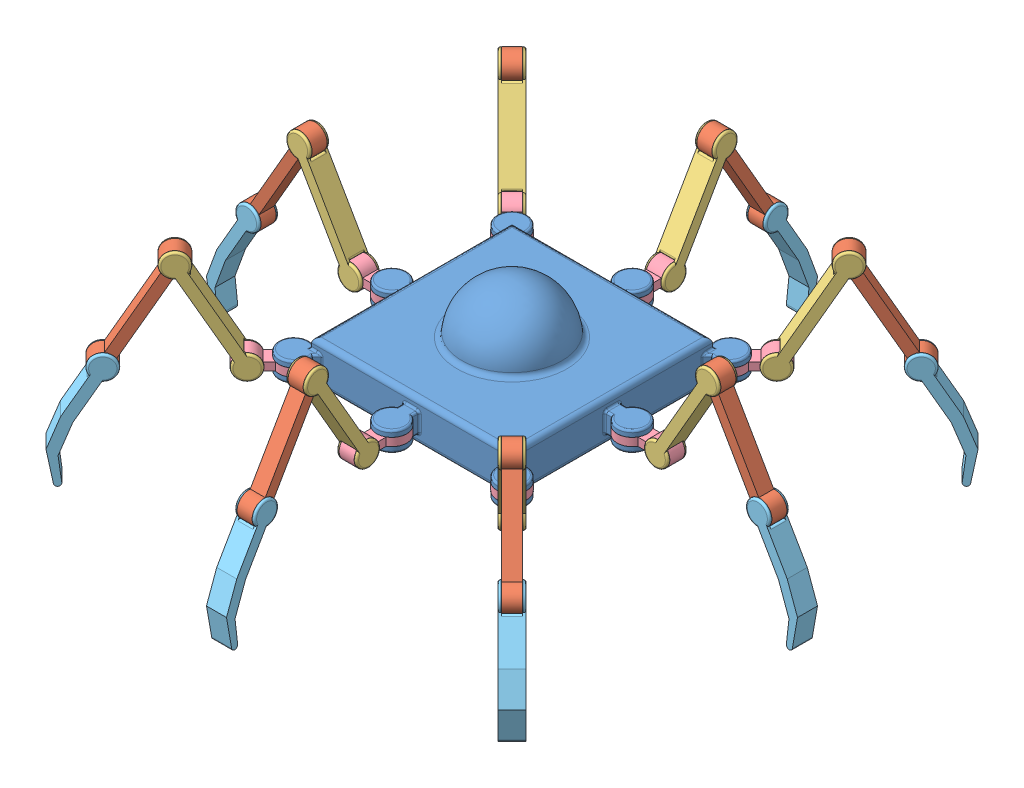
SolidWorks assembly SpiderBot_4Legs, configuration Default. Lengths in mm.
Overall size (634.89 234.57 634.89).
33 component instances, 5 part files, 146 mates.
Components (placement in the parent):
- spider_body-1: spider_body [Default] at (0 150 0) x (0 0 -1) z (0 -1 0) size (270 270 90)
- Link_C-24: Link_C [Default] at (-183.9152 176.5882 -194.5218) x (0.353553 0.866025 0.353553) z (-0.707107 0 0.707107) size (125.82 24 15)
- Link_B-24: Link_B [Default] at (-140.0258 176.5882 -154.1679) x (-0.707107 0 0.707107) z (-0.353553 0.866025 -0.353553) size (20.32 24 125.82)
- Link_A-24: Link_A [Default] at (-108.832 134 -108.832) x (-0.707107 0 -0.707107) z (0 -1 0) size (59.99 30 24)
- Link_D-24: Link_D [Default] at (-232.2874 88.4118 -218.1453) x (0.707107 0 -0.707107) z (0.353553 0.866025 0.353553) size (20.32 36.78 116.49)
- Link_C-26: Link_C [Default] at (-194.5218 176.5882 183.9152) x (0.353553 0.866025 -0.353553) z (0.707107 0 0.707107) size (125.82 24 15)
- Link_B-26: Link_B [Default] at (-154.1679 176.5882 140.0258) x (0.707107 0 0.707107) z (-0.353553 0.866025 0.353553) size (20.32 24 125.82)
- Link_A-26: Link_A [Default] at (-108.832 134 108.832) x (-0.707107 0 0.707107) z (0 -1 0) size (59.99 30 24)
- Link_D-26: Link_D [Default] at (-218.1453 88.4118 232.2874) x (-0.707107 0 -0.707107) z (0.353553 0.866025 -0.353553) size (20.32 36.78 116.49)
- Link_C-27: Link_C [Default] at (183.9152 176.5882 194.5218) x (-0.353553 0.866025 -0.353553) z (0.707107 0 -0.707107) size (125.82 24 15)
- Link_B-27: Link_B [Default] at (140.0258 176.5882 154.1679) x (0.707107 0 -0.707107) z (0.353553 0.866025 0.353553) size (20.32 24 125.82)
- Link_A-27: Link_A [Default] at (108.832 134 108.832) x (0.707107 0 0.707107) z (0 -1 0) size (59.99 30 24)
- Link_D-27: Link_D [Default] at (232.2874 88.4118 218.1453) x (-0.707107 0 0.707107) z (-0.353553 0.866025 -0.353553) size (20.32 36.78 116.49)
- Link_B-33: Link_B [Default] at (154.1679 176.5882 -140.0258) x (-0.707107 0 -0.707107) z (0.353553 0.866025 -0.353553) size (20.32 24 125.82)
- Link_D-31: Link_D [Default] at (218.1453 88.4118 -232.2874) x (0.707107 0 0.707107) z (-0.353553 0.866025 0.353553) size (20.32 36.78 116.49)
- Link_A-31: Link_A [Default] at (108.832 134 -108.832) x (0.707107 0 -0.707107) z (0 -1 0) size (59.99 30 24)
- Link_C-31: Link_C [Default] at (194.5218 176.5882 -183.9152) x (-0.353553 0.866025 0.353553) z (-0.707107 0 -0.707107) size (125.82 24 15)
- Link_D-34: Link_D [Default] at (-284.5923 88.4118 10) x (0 0 -1) z (0.5 0.866025 0) size (20.32 36.78 116.49)
- Link_A-34: Link_A [Default] at (-120 134 0) x (-1 0 0) z (0 -1 0) size (59.99 30 24)
- Link_B-36: Link_B [Default] at (-174.1146 176.5882 -10) x (0 0 1) z (-0.5 0.866025 0) size (20.32 24 125.82)
- Link_C-34: Link_C [Default] at (-233.6836 176.5882 -7.5) x (0.5 0.866025 0) z (0 0 1) size (125.82 24 15)
- Link_A-35: Link_A [Default] at (120 134 0) x (1 0 0) z (0 -1 0) size (59.99 30 24)
- Link_D-35: Link_D [Default] at (284.5923 88.4118 -10) x (0 0 1) z (-0.5 0.866025 0) size (20.32 36.78 116.49)
- Link_C-35: Link_C [Default] at (233.6836 176.5882 7.5) x (-0.5 0.866025 0) z (0 0 -1) size (125.82 24 15)
- Link_B-37: Link_B [Default] at (174.1146 176.5882 10) x (0 0 -1) z (0.5 0.866025 0) size (20.32 24 125.82)
- Link_A-36: Link_A [Default] at (0 134 120) x (0 0 1) z (0 -1 0) size (59.99 30 24)
- Link_D-36: Link_D [Default] at (10 88.4118 284.5923) x (-1 0 0) z (0 0.866025 -0.5) size (20.32 36.78 116.49)
- Link_C-36: Link_C [Default] at (-7.5 176.5882 233.6836) x (0 0.866025 -0.5) z (1 0 0) size (125.82 24 15)
- Link_B-38: Link_B [Default] at (-10 176.5882 174.1146) x (1 0 0) z (0 0.866025 0.5) size (20.32 24 125.82)
- Link_A-37: Link_A [Default] at (0 134 -120) x (0 0 -1) z (0 -1 0) size (59.99 30 24)
- Link_D-37: Link_D [Default] at (-10 88.4118 -284.5923) x (1 0 0) z (0 0.866025 0.5) size (20.32 36.78 116.49)
- Link_C-37: Link_C [Default] at (7.5 176.5882 -233.6836) x (0 0.866025 0.5) z (-1 0 0) size (125.82 24 15)
- Link_B-39: Link_B [Default] at (10 176.5882 -174.1146) x (-1 0 0) z (0 0.866025 -0.5) size (20.32 24 125.82)
Mates (geometry in assembly coordinates):
- Coincident4: coincident anti-aligned: plane of Link_B-2 through (235.0341 -365.5738 720.8033) normal (-1 0 0); plane of Link_C-2 through (235.0341 -453.7502 771.712) normal (1 0 0)
- Concentric4: concentric anti-aligned: cylinder of Link_B-2 through (220.0341 -365.5738 720.8033) axis (1 0 0) radius 4; cylinder of Link_C-2 through (235.0341 -365.5738 720.8033) axis (-1 0 0) radius 4
- Coincident5: coincident anti-aligned: plane of Link_C-2 through (235.0341 -453.7502 771.712) normal (1 0 0); plane of Link_D-2 through (235.0341 -453.7502 771.712) normal (-1 0 0)
- Concentric6: concentric aligned: cylinder of Link_C-2 through (235.0341 -453.7502 771.712) axis (-1 0 0) radius 4; cylinder of Link_D-2 through (235.0341 -453.7502 771.712) axis (-1 0 0) radius 4
- Coincident7: coincident anti-aligned: plane of Link_B-3 through (281.248 -759.0313 934.2797) normal (-1 0 0); plane of Link_C-3 through (281.248 -847.2078 985.1885) normal (1 0 0)
- Concentric7: concentric anti-aligned: cylinder of Link_B-3 through (266.248 -759.0313 934.2797) axis (1 0 0) radius 4; cylinder of Link_C-3 through (281.248 -759.0313 934.2797) axis (-1 0 0) radius 4
- Coincident8: coincident anti-aligned: plane of Link_C-3 through (281.248 -847.2078 985.1885) normal (1 0 0); plane of Link_D-3 through (281.248 -847.2078 985.1885) normal (-1 0 0)
- Concentric9: concentric aligned: cylinder of Link_C-3 through (281.248 -847.2078 985.1885) axis (-1 0 0) radius 4; cylinder of Link_D-3 through (281.248 -847.2078 985.1885) axis (-1 0 0) radius 4
- Coincident10: coincident anti-aligned: plane of Link_B-4 through (178.5336 -465.5708 822.703) normal (-1 0 0); plane of Link_C-4 through (178.5336 -553.7473 873.6117) normal (1 0 0)
- Concentric10: concentric anti-aligned: cylinder of Link_B-4 through (163.5336 -465.5708 822.703) axis (1 0 0) radius 4; cylinder of Link_C-4 through (178.5336 -465.5708 822.703) axis (-1 0 0) radius 4
- Coincident11: coincident anti-aligned: plane of Link_C-4 through (178.5336 -553.7473 873.6117) normal (1 0 0); plane of Link_D-4 through (178.5336 -553.7473 873.6117) normal (-1 0 0)
- Concentric12: concentric aligned: cylinder of Link_C-4 through (178.5336 -553.7473 873.6117) axis (-1 0 0) radius 4; cylinder of Link_D-4 through (178.5336 -553.7473 873.6117) axis (-1 0 0) radius 4
- Coincident13: coincident anti-aligned: plane of Link_B-5 through (262.376 -1013.0932 1106.1332) normal (-1 0 0); plane of Link_C-5 through (262.376 -1101.2696 1157.0419) normal (1 0 0)
- Concentric13: concentric anti-aligned: cylinder of Link_B-5 through (247.376 -1013.0932 1106.1332) axis (1 0 0) radius 4; cylinder of Link_C-5 through (262.376 -1013.0932 1106.1332) axis (-1 0 0) radius 4
- Coincident14: coincident anti-aligned: plane of Link_C-5 through (262.376 -1101.2696 1157.0419) normal (1 0 0); plane of Link_D-5 through (262.376 -1101.2696 1157.0419) normal (-1 0 0)
- Concentric15: concentric aligned: cylinder of Link_C-5 through (262.376 -1101.2696 1157.0419) axis (-1 0 0) radius 4; cylinder of Link_D-5 through (262.376 -1101.2696 1157.0419) axis (-1 0 0) radius 4
- Coincident16: coincident anti-aligned: plane of Link_B-6 through (534.9738 -1642.7072 1309.0583) normal (-1 0 0); plane of Link_C-6 through (534.9738 -1730.8837 1359.9671) normal (1 0 0)
- Concentric16: concentric anti-aligned: cylinder of Link_B-6 through (519.9738 -1642.7072 1309.0583) axis (1 0 0) radius 4; cylinder of Link_C-6 through (534.9738 -1642.7072 1309.0583) axis (-1 0 0) radius 4
- Coincident17: coincident anti-aligned: plane of Link_C-6 through (534.9738 -1730.8837 1359.9671) normal (1 0 0); plane of Link_D-6 through (534.9738 -1730.8837 1359.9671) normal (-1 0 0)
- Concentric18: concentric aligned: cylinder of Link_C-6 through (534.9738 -1730.8837 1359.9671) axis (-1 0 0) radius 4; cylinder of Link_D-6 through (534.9738 -1730.8837 1359.9671) axis (-1 0 0) radius 4
- Coincident19: coincident anti-aligned: plane of Link_B-7 through (-306.3909 -269.9837 1039.0888) normal (-1 0 0); plane of Link_C-7 through (-306.3909 -358.1602 1089.9975) normal (1 0 0)
- Concentric19: concentric anti-aligned: cylinder of Link_B-7 through (-321.3909 -269.9837 1039.0888) axis (1 0 0) radius 4; cylinder of Link_C-7 through (-306.3909 -269.9837 1039.0888) axis (-1 0 0) radius 4
- Coincident20: coincident anti-aligned: plane of Link_C-7 through (-306.3909 -358.1602 1089.9975) normal (1 0 0); plane of Link_D-7 through (-306.3909 -358.1602 1089.9975) normal (-1 0 0)
- Concentric21: concentric aligned: cylinder of Link_C-7 through (-306.3909 -358.1602 1089.9975) axis (-1 0 0) radius 4; cylinder of Link_D-7 through (-306.3909 -358.1602 1089.9975) axis (-1 0 0) radius 4
- Coincident22: coincident anti-aligned: plane of Link_B-8 through (-311.8852 -488.0983 1179.1514) normal (-1 0 0); plane of Link_C-8 through (-311.8852 -576.2747 1230.0601) normal (1 0 0)
- Concentric22: concentric anti-aligned: cylinder of Link_B-8 through (-326.8852 -488.0983 1179.1514) axis (1 0 0) radius 4; cylinder of Link_C-8 through (-311.8852 -488.0983 1179.1514) axis (-1 0 0) radius 4
- Coincident23: coincident anti-aligned: plane of Link_C-8 through (-311.8852 -576.2747 1230.0601) normal (1 0 0); plane of Link_D-8 through (-311.8852 -576.2747 1230.0601) normal (-1 0 0)
- Concentric24: concentric aligned: cylinder of Link_C-8 through (-311.8852 -576.2747 1230.0601) axis (-1 0 0) radius 4; cylinder of Link_D-8 through (-311.8852 -576.2747 1230.0601) axis (-1 0 0) radius 4
- Coincident25: coincident anti-aligned: plane of Link_B-9 through (-611.4857 -390.9688 1327.6493) normal (-1 0 0); plane of Link_C-9 through (-611.4857 -479.1453 1378.558) normal (1 0 0)
- Concentric25: concentric anti-aligned: cylinder of Link_B-9 through (-626.4857 -390.9688 1327.6493) axis (1 0 0) radius 4; cylinder of Link_C-9 through (-611.4857 -390.9688 1327.6493) axis (-1 0 0) radius 4
- Coincident26: coincident anti-aligned: plane of Link_C-9 through (-611.4857 -479.1453 1378.558) normal (1 0 0); plane of Link_D-9 through (-611.4857 -479.1453 1378.558) normal (-1 0 0)
- Concentric27: concentric aligned: cylinder of Link_C-9 through (-611.4857 -479.1453 1378.558) axis (-1 0 0) radius 4; cylinder of Link_D-9 through (-611.4857 -479.1453 1378.558) axis (-1 0 0) radius 4
- Coincident28: coincident anti-aligned: plane of Link_B-10 through (-139.42 -657.5126 1164.5577) normal (-1 0 0); plane of Link_C-10 through (-139.42 -745.689 1215.4664) normal (1 0 0)
- Concentric28: concentric anti-aligned: cylinder of Link_B-10 through (-154.42 -657.5126 1164.5577) axis (1 0 0) radius 4; cylinder of Link_C-10 through (-139.42 -657.5126 1164.5577) axis (-1 0 0) radius 4
- Coincident29: coincident anti-aligned: plane of Link_C-10 through (-139.42 -745.689 1215.4664) normal (1 0 0); plane of Link_D-10 through (-139.42 -745.689 1215.4664) normal (-1 0 0)
- Concentric30: concentric aligned: cylinder of Link_C-10 through (-139.42 -745.689 1215.4664) axis (-1 0 0) radius 4; cylinder of Link_D-10 through (-139.42 -745.689 1215.4664) axis (-1 0 0) radius 4
- Coincident31: coincident anti-aligned: plane of Link_B-11 through (-139.42 -657.5126 1164.5577) normal (-1 0 0); plane of Link_C-11 through (-139.42 -745.689 1215.4664) normal (1 0 0)
- Concentric31: concentric anti-aligned: cylinder of Link_B-11 through (-154.42 -657.5126 1164.5577) axis (1 0 0) radius 4; cylinder of Link_C-11 through (-139.42 -657.5126 1164.5577) axis (-1 0 0) radius 4
- Coincident32: coincident anti-aligned: plane of Link_C-11 through (-139.42 -745.689 1215.4664) normal (1 0 0); plane of Link_D-11 through (-139.42 -745.689 1215.4664) normal (-1 0 0)
- Concentric33: concentric aligned: cylinder of Link_C-11 through (-139.42 -745.689 1215.4664) axis (-1 0 0) radius 4; cylinder of Link_D-11 through (-139.42 -745.689 1215.4664) axis (-1 0 0) radius 4
- Coincident34: coincident anti-aligned: plane of Link_B-12 through (-94.7509 -804.43 1225.1322) normal (-1 0 0); plane of Link_C-12 through (-94.7509 -892.6065 1276.0409) normal (1 0 0)
- Concentric34: concentric anti-aligned: cylinder of Link_B-12 through (-109.7509 -804.43 1225.1322) axis (1 0 0) radius 4; cylinder of Link_C-12 through (-94.7509 -804.43 1225.1322) axis (-1 0 0) radius 4
- Coincident35: coincident anti-aligned: plane of Link_C-12 through (-94.7509 -892.6065 1276.0409) normal (1 0 0); plane of Link_D-12 through (-94.7509 -892.6065 1276.0409) normal (-1 0 0)
- Concentric36: concentric aligned: cylinder of Link_C-12 through (-94.7509 -892.6065 1276.0409) axis (-1 0 0) radius 4; cylinder of Link_D-12 through (-94.7509 -892.6065 1276.0409) axis (-1 0 0) radius 4
- Concentric78: concentric anti-aligned: cylinder of Link_C-24 through (-173.461 218.1765 -162.8544) axis (0.707107 0 -0.707107) radius 4; cylinder of Link_B-24 through (-162.8544 218.1765 -173.461) axis (-0.707107 0 0.707107) radius 4
- Concentric79: concentric anti-aligned: cylinder of Link_B-24 through (-126.8565 130 -137.4631) axis (-0.707107 0 0.707107) radius 4; cylinder of Link_A-24 through (-142.7664 130 -121.5532) axis (0.707107 0 -0.707107) radius 5
- Coincident86: coincident anti-aligned: plane of Link_B-24 through (-137.4631 130 -126.8565) normal (0.707107 0 -0.707107); plane of Link_A-24 through (-123.3209 126 -112.7143) normal (-0.707107 0 0.707107)
- Coincident87: coincident anti-aligned: plane of Link_C-24 through (-198.8522 130 -209.4588) normal (0.707107 0 -0.707107); plane of Link_B-24 through (-162.8544 218.1765 -173.461) normal (-0.707107 0 0.707107)
- Coincident88: coincident anti-aligned: plane of Link_C-24 through (-209.4588 130 -198.8522) normal (-0.707107 0 0.707107); plane of Link_B-24 through (-173.461 218.1765 -162.8544) normal (0.707107 0 -0.707107)
- Coincident89: coincident anti-aligned: plane of Link_C-24 through (-198.8522 130 -209.4588) normal (0.707107 0 -0.707107); plane of Link_D-24 through (-198.8522 130 -209.4588) normal (-0.707107 0 0.707107)
- Concentric80: concentric aligned: cylinder of Link_C-24 through (-209.4588 130 -198.8522) axis (0.707107 0 -0.707107) radius 4; cylinder of Link_D-24 through (-209.4588 130 -198.8522) axis (0.707107 0 -0.707107) radius 4
- Coincident90: coincident anti-aligned: plane of Link_B-24 through (-126.8565 130 -137.4631) normal (-0.707107 0 0.707107); plane of Link_A-24 through (-112.7143 126 -123.3209) normal (0.707107 0 -0.707107)
- Coincident91: coincident anti-aligned: plane of Link_C-24 through (-209.4588 130 -198.8522) normal (-0.707107 0 0.707107); plane of Link_D-24 through (-209.4588 130 -198.8522) normal (0.707107 0 -0.707107)
- Concentric84: concentric anti-aligned: cylinder of Link_C-26 through (-162.8544 218.1765 173.461) axis (-0.707107 0 -0.707107) radius 4; cylinder of Link_B-26 through (-173.461 218.1765 162.8544) axis (0.707107 0 0.707107) radius 4
- Concentric85: concentric anti-aligned: cylinder of Link_B-26 through (-137.4631 130 126.8565) axis (0.707107 0 0.707107) radius 4; cylinder of Link_A-26 through (-121.5532 130 142.7664) axis (-0.707107 0 -0.707107) radius 5
- Coincident98: coincident anti-aligned: plane of Link_B-26 through (-126.8565 130 137.4631) normal (-0.707107 0 -0.707107); plane of Link_A-26 through (-112.7143 126 123.3209) normal (0.707107 0 0.707107)
- Coincident99: coincident anti-aligned: plane of Link_C-26 through (-209.4588 130 198.8522) normal (-0.707107 0 -0.707107); plane of Link_B-26 through (-173.461 218.1765 162.8544) normal (0.707107 0 0.707107)
- Coincident100: coincident anti-aligned: plane of Link_C-26 through (-198.8522 130 209.4588) normal (0.707107 0 0.707107); plane of Link_B-26 through (-162.8544 218.1765 173.461) normal (-0.707107 0 -0.707107)
- Coincident101: coincident anti-aligned: plane of Link_C-26 through (-209.4588 130 198.8522) normal (-0.707107 0 -0.707107); plane of Link_D-26 through (-209.4588 130 198.8522) normal (0.707107 0 0.707107)
- Concentric86: concentric aligned: cylinder of Link_C-26 through (-198.8522 130 209.4588) axis (-0.707107 0 -0.707107) radius 4; cylinder of Link_D-26 through (-198.8522 130 209.4588) axis (-0.707107 0 -0.707107) radius 4
- Coincident102: coincident anti-aligned: plane of Link_B-26 through (-137.4631 130 126.8565) normal (0.707107 0 0.707107); plane of Link_A-26 through (-123.3209 126 112.7143) normal (-0.707107 0 -0.707107)
- Coincident103: coincident anti-aligned: plane of Link_C-26 through (-198.8522 130 209.4588) normal (0.707107 0 0.707107); plane of Link_D-26 through (-198.8522 130 209.4588) normal (-0.707107 0 -0.707107)
- Concentric87: concentric anti-aligned: cylinder of Link_C-27 through (173.461 218.1765 162.8544) axis (-0.707107 0 0.707107) radius 4; cylinder of Link_B-27 through (162.8544 218.1765 173.461) axis (0.707107 0 -0.707107) radius 4
- Concentric88: concentric anti-aligned: cylinder of Link_B-27 through (126.8565 130 137.4631) axis (0.707107 0 -0.707107) radius 4; cylinder of Link_A-27 through (142.7664 130 121.5532) axis (-0.707107 0 0.707107) radius 5
- Coincident104: coincident anti-aligned: plane of Link_B-27 through (137.4631 130 126.8565) normal (-0.707107 0 0.707107); plane of Link_A-27 through (123.3209 126 112.7143) normal (0.707107 0 -0.707107)
- Coincident105: coincident anti-aligned: plane of Link_C-27 through (198.8522 130 209.4588) normal (-0.707107 0 0.707107); plane of Link_B-27 through (162.8544 218.1765 173.461) normal (0.707107 0 -0.707107)
- Coincident106: coincident anti-aligned: plane of Link_C-27 through (209.4588 130 198.8522) normal (0.707107 0 -0.707107); plane of Link_B-27 through (173.461 218.1765 162.8544) normal (-0.707107 0 0.707107)
- Coincident107: coincident anti-aligned: plane of Link_C-27 through (198.8522 130 209.4588) normal (-0.707107 0 0.707107); plane of Link_D-27 through (198.8522 130 209.4588) normal (0.707107 0 -0.707107)
- Concentric89: concentric aligned: cylinder of Link_C-27 through (209.4588 130 198.8522) axis (-0.707107 0 0.707107) radius 4; cylinder of Link_D-27 through (209.4588 130 198.8522) axis (-0.707107 0 0.707107) radius 4
- Coincident108: coincident anti-aligned: plane of Link_B-27 through (126.8565 130 137.4631) normal (0.707107 0 -0.707107); plane of Link_A-27 through (112.7143 126 123.3209) normal (-0.707107 0 0.707107)
- Coincident109: coincident anti-aligned: plane of Link_C-27 through (209.4588 130 198.8522) normal (0.707107 0 -0.707107); plane of Link_D-27 through (209.4588 130 198.8522) normal (-0.707107 0 0.707107)
- Coincident124: coincident anti-aligned: plane of spider_body-1 through (108.832 134 108.832) normal (0 -1 0); plane of Link_A-27 through (108.832 134 108.832) normal (0 1 0)
- Coincident125: coincident anti-aligned: plane of spider_body-1 through (108.832 126 108.832) normal (0 1 0); plane of Link_A-27 through (108.832 126 108.832) normal (0 -1 0)
- Concentric97: concentric anti-aligned: cylinder of spider_body-1 through (108.832 134 108.832) axis (0 -1 0) radius 10; cylinder of Link_A-27 through (108.832 126 108.832) axis (0 1 0) radius 10
- Coincident126: coincident anti-aligned: plane of spider_body-1 through (-108.832 134 108.832) normal (0 -1 0); plane of Link_A-26 through (-108.832 134 108.832) normal (0 1 0)
- Coincident127: coincident anti-aligned: plane of spider_body-1 through (-108.832 126 108.832) normal (0 1 0); plane of Link_A-26 through (-108.832 126 108.832) normal (0 -1 0)
- Concentric98: concentric anti-aligned: cylinder of spider_body-1 through (-108.832 134 108.832) axis (0 -1 0) radius 10; cylinder of Link_A-26 through (-108.832 126 108.832) axis (0 1 0) radius 10
- Coincident138: coincident anti-aligned: plane of Link_B-33 through (162.8544 218.1765 -173.461) normal (0.707107 0 0.707107); plane of Link_C-31 through (198.8522 130 -209.4588) normal (-0.707107 0 -0.707107)
- Coincident139: coincident anti-aligned: plane of Link_D-31 through (209.4588 130 -198.8522) normal (-0.707107 0 -0.707107); plane of Link_C-31 through (209.4588 130 -198.8522) normal (0.707107 0 0.707107)
- Coincident140: coincident anti-aligned: plane of Link_D-31 through (198.8522 130 -209.4588) normal (0.707107 0 0.707107); plane of Link_C-31 through (198.8522 130 -209.4588) normal (-0.707107 0 -0.707107)
- Concentric104: concentric aligned: cylinder of Link_D-31 through (198.8522 130 -209.4588) axis (0.707107 0 0.707107) radius 4; cylinder of Link_C-31 through (198.8522 130 -209.4588) axis (0.707107 0 0.707107) radius 4
- Coincident141: coincident anti-aligned: plane of Link_B-33 through (137.4631 130 -126.8565) normal (-0.707107 0 -0.707107); plane of Link_A-31 through (123.3209 126 -112.7143) normal (0.707107 0 0.707107)
- Concentric105: concentric anti-aligned: cylinder of Link_B-33 through (173.461 218.1765 -162.8544) axis (-0.707107 0 -0.707107) radius 4; cylinder of Link_C-31 through (162.8544 218.1765 -173.461) axis (0.707107 0 0.707107) radius 4
- Concentric106: concentric anti-aligned: cylinder of Link_B-33 through (137.4631 130 -126.8565) axis (-0.707107 0 -0.707107) radius 4; cylinder of Link_A-31 through (121.5532 130 -142.7664) axis (0.707107 0 0.707107) radius 5
- Coincident142: coincident anti-aligned: plane of Link_B-33 through (126.8565 130 -137.4631) normal (0.707107 0 0.707107); plane of Link_A-31 through (112.7143 126 -123.3209) normal (-0.707107 0 -0.707107)
- Coincident143: coincident anti-aligned: plane of Link_B-33 through (173.461 218.1765 -162.8544) normal (-0.707107 0 -0.707107); plane of Link_C-31 through (209.4588 130 -198.8522) normal (0.707107 0 0.707107)
- Coincident146: coincident anti-aligned: plane of spider_body-1 through (108.832 134 -108.832) normal (0 -1 0); plane of Link_A-31 through (108.832 134 -108.832) normal (0 1 0)
- Coincident147: coincident anti-aligned: plane of spider_body-1 through (108.832 126 -108.832) normal (0 1 0); plane of Link_A-31 through (108.832 126 -108.832) normal (0 -1 0)
- Concentric108: concentric anti-aligned: cylinder of spider_body-1 through (108.832 134 -108.832) axis (0 -1 0) radius 10; cylinder of Link_A-31 through (108.832 126 -108.832) axis (0 1 0) radius 10
- Coincident148: coincident anti-aligned: plane of spider_body-1 through (-108.832 134 -108.832) normal (0 -1 0); plane of Link_A-24 through (-108.832 134 -108.832) normal (0 1 0)
- Coincident149: coincident anti-aligned: plane of spider_body-1 through (-108.832 126 -108.832) normal (0 1 0); plane of Link_A-24 through (-108.832 126 -108.832) normal (0 -1 0)
- Concentric109: concentric anti-aligned: cylinder of spider_body-1 through (-108.832 134 -108.832) axis (0 -1 0) radius 10; cylinder of Link_A-24 through (-108.832 126 -108.832) axis (0 1 0) radius 10
- Concentric111: concentric anti-aligned: cylinder of Link_A-32 through (-1752.5654 2022.5976 -1745.769) axis (0.707107 0 -0.707107) radius 5; cylinder of Link_B-34 through (-1736.6555 2022.5976 -1761.6789) axis (-0.707107 0 0.707107) radius 4
- Coincident151: coincident anti-aligned: plane of Link_B-34 through (-1783.26 2110.774 -1787.0702) normal (0.707107 0 -0.707107); plane of Link_C-32 through (-1819.2579 2022.5976 -1823.0681) normal (-0.707107 0 0.707107)
- Concentric112: concentric anti-aligned: cylinder of Link_B-34 through (-1772.6534 2110.774 -1797.6768) axis (-0.707107 0 0.707107) radius 4; cylinder of Link_C-32 through (-1783.26 2110.774 -1787.0702) axis (0.707107 0 -0.707107) radius 4
- Coincident153: coincident anti-aligned: plane of Link_A-32 through (-1733.12 2018.5976 -1736.9302) normal (-0.707107 0 0.707107); plane of Link_B-34 through (-1747.2621 2022.5976 -1751.0723) normal (0.707107 0 -0.707107)
- Coincident154: coincident anti-aligned: plane of Link_B-34 through (-1772.6534 2110.774 -1797.6768) normal (-0.707107 0 0.707107); plane of Link_C-32 through (-1808.6513 2022.5976 -1833.6747) normal (0.707107 0 -0.707107)
- Coincident155: coincident anti-aligned: plane of Link_A-32 through (-1722.5134 2018.5976 -1747.5368) normal (0.707107 0 -0.707107); plane of Link_B-34 through (-1736.6555 2022.5976 -1761.6789) normal (-0.707107 0 0.707107)
- Concentric116: concentric aligned: cylinder of Link_D-34 through (-254.8078 130 7.5) axis (0 0 -1) radius 4; cylinder of Link_C-34 through (-254.8078 130 7.5) axis (0 0 -1) radius 4
- Coincident162: coincident anti-aligned: plane of Link_D-34 through (-254.8078 130 7.5) normal (0 0 -1); plane of Link_C-34 through (-254.8078 130 7.5) normal (0 0 1)
- Concentric117: concentric anti-aligned: cylinder of Link_A-34 through (-152.9904 130 15) axis (0 0 -1) radius 5; cylinder of Link_B-36 through (-152.9904 130 -7.5) axis (0 0 1) radius 4
- Coincident163: coincident anti-aligned: plane of Link_B-36 through (-203.8991 218.1765 7.5) normal (0 0 -1); plane of Link_C-34 through (-254.8078 130 7.5) normal (0 0 1)
- Concentric118: concentric anti-aligned: cylinder of Link_B-36 through (-203.8991 218.1765 -7.5) axis (0 0 1) radius 4; cylinder of Link_C-34 through (-203.8991 218.1765 7.5) axis (0 0 -1) radius 4
- Coincident164: coincident anti-aligned: plane of Link_D-34 through (-254.8078 130 -7.5) normal (0 0 1); plane of Link_C-34 through (-254.8078 130 -7.5) normal (0 0 -1)
- Coincident165: coincident anti-aligned: plane of Link_A-34 through (-132.9904 126 7.5) normal (0 0 1); plane of Link_B-36 through (-152.9904 130 7.5) normal (0 0 -1)
- Coincident166: coincident anti-aligned: plane of Link_B-36 through (-203.8991 218.1765 -7.5) normal (0 0 1); plane of Link_C-34 through (-254.8078 130 -7.5) normal (0 0 -1)
- Coincident167: coincident anti-aligned: plane of Link_A-34 through (-132.9904 126 -7.5) normal (0 0 -1); plane of Link_B-36 through (-152.9904 130 -7.5) normal (0 0 1)
- Concentric119: concentric aligned: cylinder of Link_D-35 through (254.8078 130 -7.5) axis (0 0 1) radius 4; cylinder of Link_C-35 through (254.8078 130 -7.5) axis (0 0 1) radius 4
- Concentric120: concentric anti-aligned: cylinder of Link_C-35 through (203.8991 218.1765 -7.5) axis (0 0 1) radius 4; cylinder of Link_B-37 through (203.8991 218.1765 7.5) axis (0 0 -1) radius 4
- Coincident168: coincident anti-aligned: plane of Link_A-35 through (132.9904 126 7.5) normal (0 0 1); plane of Link_B-37 through (152.9904 130 7.5) normal (0 0 -1)
- Coincident169: coincident anti-aligned: plane of Link_A-35 through (132.9904 126 -7.5) normal (0 0 -1); plane of Link_B-37 through (152.9904 130 -7.5) normal (0 0 1)
- Coincident170: coincident anti-aligned: plane of Link_D-35 through (254.8078 130 -7.5) normal (0 0 1); plane of Link_C-35 through (254.8078 130 -7.5) normal (0 0 -1)
- Concentric121: concentric anti-aligned: cylinder of Link_A-35 through (152.9904 130 -15) axis (0 0 1) radius 5; cylinder of Link_B-37 through (152.9904 130 7.5) axis (0 0 -1) radius 4
- Coincident171: coincident anti-aligned: plane of Link_C-35 through (254.8078 130 -7.5) normal (0 0 -1); plane of Link_B-37 through (203.8991 218.1765 -7.5) normal (0 0 1)
- Coincident172: coincident anti-aligned: plane of Link_D-35 through (254.8078 130 7.5) normal (0 0 -1); plane of Link_C-35 through (254.8078 130 7.5) normal (0 0 1)
- Coincident173: coincident anti-aligned: plane of Link_C-35 through (254.8078 130 7.5) normal (0 0 1); plane of Link_B-37 through (203.8991 218.1765 7.5) normal (0 0 -1)
- Concentric122: concentric aligned: cylinder of Link_D-36 through (7.5 130 254.8078) axis (-1 0 0) radius 4; cylinder of Link_C-36 through (7.5 130 254.8078) axis (-1 0 0) radius 4
- Concentric123: concentric anti-aligned: cylinder of Link_C-36 through (7.5 218.1765 203.8991) axis (-1 0 0) radius 4; cylinder of Link_B-38 through (-7.5 218.1765 203.8991) axis (1 0 0) radius 4
- Coincident174: coincident anti-aligned: plane of Link_A-36 through (-7.5 126 132.9904) normal (-1 0 0); plane of Link_B-38 through (-7.5 130 152.9904) normal (1 0 0)
- Coincident175: coincident anti-aligned: plane of Link_A-36 through (7.5 126 132.9904) normal (1 0 0); plane of Link_B-38 through (7.5 130 152.9904) normal (-1 0 0)
- Coincident176: coincident anti-aligned: plane of Link_D-36 through (7.5 130 254.8078) normal (-1 0 0); plane of Link_C-36 through (7.5 130 254.8078) normal (1 0 0)
- Concentric124: concentric anti-aligned: cylinder of Link_A-36 through (15 130 152.9904) axis (-1 0 0) radius 5; cylinder of Link_B-38 through (-7.5 130 152.9904) axis (1 0 0) radius 4
- Coincident177: coincident anti-aligned: plane of Link_C-36 through (7.5 130 254.8078) normal (1 0 0); plane of Link_B-38 through (7.5 218.1765 203.8991) normal (-1 0 0)
- Coincident178: coincident anti-aligned: plane of Link_D-36 through (-7.5 130 254.8078) normal (1 0 0); plane of Link_C-36 through (-7.5 130 254.8078) normal (-1 0 0)
- Coincident179: coincident anti-aligned: plane of Link_C-36 through (-7.5 130 254.8078) normal (-1 0 0); plane of Link_B-38 through (-7.5 218.1765 203.8991) normal (1 0 0)
- Concentric125: concentric aligned: cylinder of Link_D-37 through (-7.5 130 -254.8078) axis (1 0 0) radius 4; cylinder of Link_C-37 through (-7.5 130 -254.8078) axis (1 0 0) radius 4
- Concentric126: concentric anti-aligned: cylinder of Link_C-37 through (-7.5 218.1765 -203.8991) axis (1 0 0) radius 4; cylinder of Link_B-39 through (7.5 218.1765 -203.8991) axis (-1 0 0) radius 4
- Coincident180: coincident anti-aligned: plane of Link_A-37 through (7.5 126 -132.9904) normal (1 0 0); plane of Link_B-39 through (7.5 130 -152.9904) normal (-1 0 0)
- Coincident181: coincident anti-aligned: plane of Link_A-37 through (-7.5 126 -132.9904) normal (-1 0 0); plane of Link_B-39 through (-7.5 130 -152.9904) normal (1 0 0)
- Coincident182: coincident anti-aligned: plane of Link_D-37 through (-7.5 130 -254.8078) normal (1 0 0); plane of Link_C-37 through (-7.5 130 -254.8078) normal (-1 0 0)
- Concentric127: concentric anti-aligned: cylinder of Link_A-37 through (-15 130 -152.9904) axis (1 0 0) radius 5; cylinder of Link_B-39 through (7.5 130 -152.9904) axis (-1 0 0) radius 4
- Coincident183: coincident anti-aligned: plane of Link_C-37 through (-7.5 130 -254.8078) normal (-1 0 0); plane of Link_B-39 through (-7.5 218.1765 -203.8991) normal (1 0 0)
- Coincident184: coincident anti-aligned: plane of Link_D-37 through (7.5 130 -254.8078) normal (-1 0 0); plane of Link_C-37 through (7.5 130 -254.8078) normal (1 0 0)
- Coincident185: coincident anti-aligned: plane of Link_C-37 through (7.5 130 -254.8078) normal (1 0 0); plane of Link_B-39 through (7.5 218.1765 -203.8991) normal (-1 0 0)
- Coincident187: coincident anti-aligned: plane of spider_body-1 through (-120 134 0) normal (0 -1 0); plane of Link_A-34 through (-120 134 0) normal (0 1 0)
- Coincident188: coincident anti-aligned: plane of spider_body-1 through (-120 126 0) normal (0 1 0); plane of Link_A-34 through (-120 126 0) normal (0 -1 0)
- Concentric129: concentric anti-aligned: cylinder of spider_body-1 through (-120 134 0) axis (0 -1 0) radius 10; cylinder of Link_A-34 through (-120 126 0) axis (0 1 0) radius 10
- Coincident189: coincident anti-aligned: plane of spider_body-1 through (0 134 -120) normal (0 -1 0); plane of Link_A-37 through (0 134 -120) normal (0 1 0)
- Coincident190: coincident anti-aligned: plane of spider_body-1 through (0 126 -120) normal (0 1 0); plane of Link_A-37 through (0 126 -120) normal (0 -1 0)
- Concentric130: concentric anti-aligned: cylinder of spider_body-1 through (0 134 -120) axis (0 -1 0) radius 10; cylinder of Link_A-37 through (0 126 -120) axis (0 1 0) radius 10
- Coincident191: coincident anti-aligned: plane of spider_body-1 through (120 134 0) normal (0 -1 0); plane of Link_A-35 through (120 134 0) normal (0 1 0)
- Coincident192: coincident anti-aligned: plane of spider_body-1 through (120 126 0) normal (0 1 0); plane of Link_A-35 through (120 126 0) normal (0 -1 0)
- Concentric131: concentric anti-aligned: cylinder of spider_body-1 through (120 134 0) axis (0 -1 0) radius 10; cylinder of Link_A-35 through (120 126 0) axis (0 1 0) radius 10
- Coincident193: coincident anti-aligned: plane of spider_body-1 through (0 134 120) normal (0 -1 0); plane of Link_A-36 through (0 134 120) normal (0 1 0)
- Coincident194: coincident anti-aligned: plane of spider_body-1 through (0 126 120) normal (0 1 0); plane of Link_A-36 through (0 126 120) normal (0 -1 0)
- Concentric132: concentric anti-aligned: cylinder of spider_body-1 through (0 134 120) axis (0 -1 0) radius 10; cylinder of Link_A-36 through (0 126 120) axis (0 1 0) radius 10
